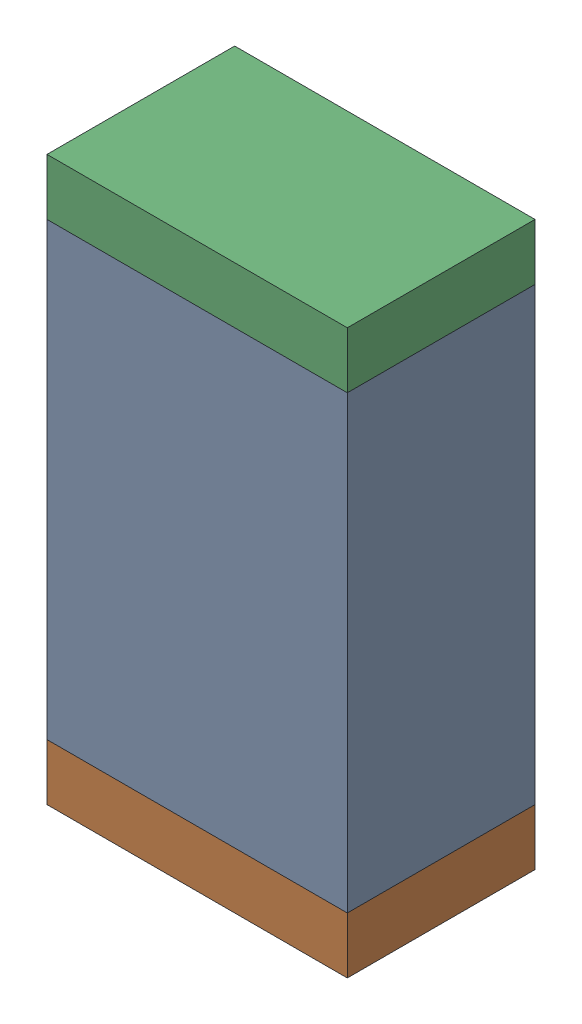
SolidWorks assembly C27, configuration Default. Lengths in mm.
Overall size (0.8 1.5 0.5).
6 component instances, 2 part files, 0 mates.
Components (placement in the parent):
- 810156976-1: 810156976 [Default] at (123.15 27.3 0) size (0.8 1.2 0.5)
  - Extruded_6-1: Extruded_6 [Default] at origin size (0.8 1.2 0.5)
- 810156592-1: 810156592 [Default] at (123.15 26.625 0) size (0.8 0.15 0.5)
  - Extruded_7-1: Extruded_7 [Default] at origin size (0.8 0.15 0.5)
- 810156592-2: 810156592 [Default] at (123.15 27.975 0) size (0.8 0.15 0.5)
  - Extruded_7-1: Extruded_7 [Default] at origin size (0.8 0.15 0.5)
